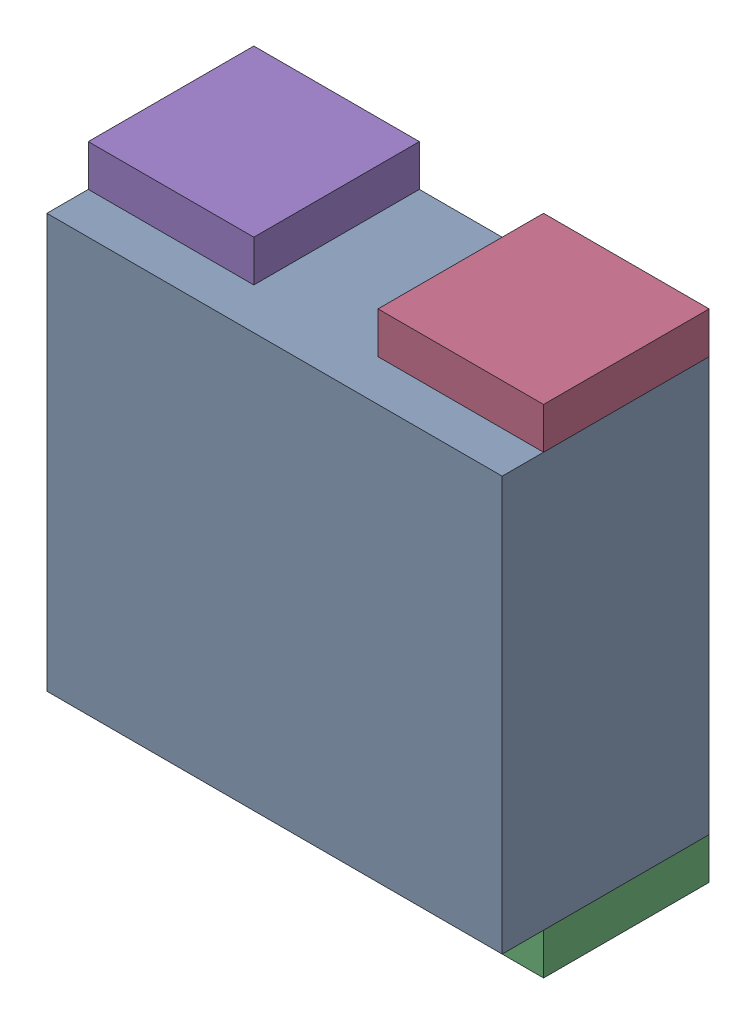
SolidWorks assembly RN25, configuration Default. Lengths in mm.
Overall size (1.1 1.2 0.5).
10 component instances, 2 part files, 0 mates.
Components (placement in the parent):
- 810156720-1: 810156720 [Default] at (127.9 18.4 0) size (1.1 1 0.5)
  - Extruded_13-1: Extruded_13 [Default] at origin size (1.1 1 0.5)
- 810157616-1: 810157616 [Default] at (127.55 17.85 0) size (0.4 0.1 0.4)
  - Extruded_12-1: Extruded_12 [Default] at origin size (0.4 0.1 0.4)
- 810157616-2: 810157616 [Default] at (128.25 17.85 0) size (0.4 0.1 0.4)
  - Extruded_12-1: Extruded_12 [Default] at origin size (0.4 0.1 0.4)
- 810157616-3: 810157616 [Default] at (128.25 18.95 0) size (0.4 0.1 0.4)
  - Extruded_12-1: Extruded_12 [Default] at origin size (0.4 0.1 0.4)
- 810157616-4: 810157616 [Default] at (127.55 18.95 0) size (0.4 0.1 0.4)
  - Extruded_12-1: Extruded_12 [Default] at origin size (0.4 0.1 0.4)
